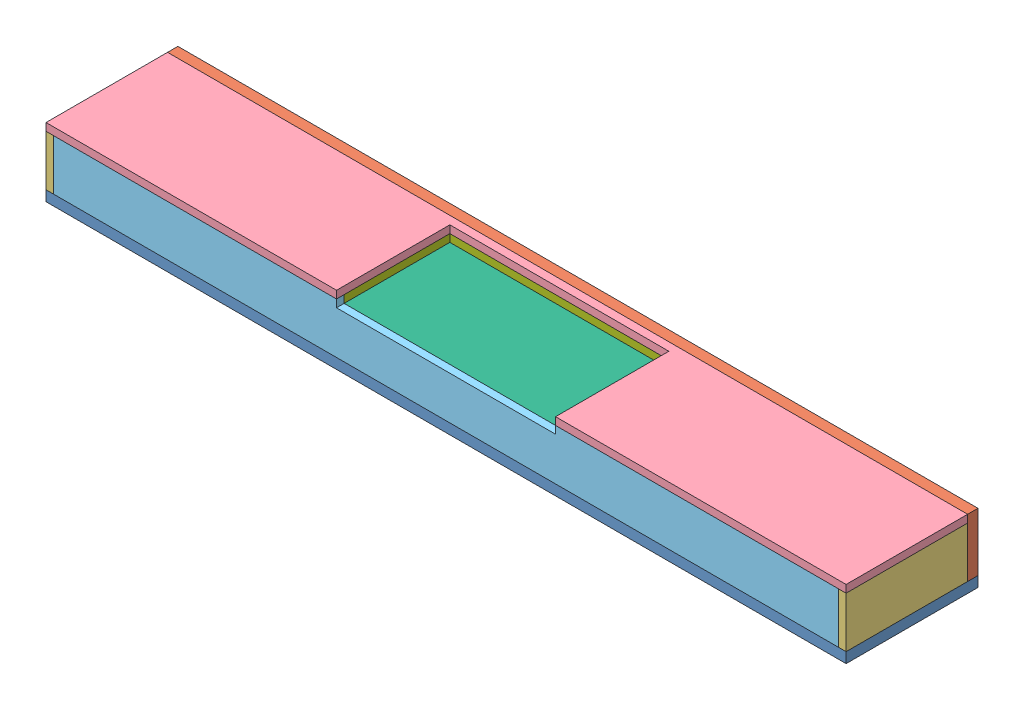
SolidWorks assembly racebaan omhulsel, configuration Default. Lengths in mm.
Overall size (316 27.1 52.1).
8 component instances, 7 part files, 21 mates.
Components (placement in the parent):
- onderstuk racebaan-1: onderstuk racebaan [Default] at (126.0031 144.5271 253.4798) size (316 4.3 52.1)
- zijkant racebaan-1: zijkant racebaan [Default] at (126.0031 156.0271 231.5298) x (1 0 0) z (0 -1 0) size (316 4.3 23)
- doorzichtig zijkant racebaan-1: doorzichtig zijkant racebaan [Default] at (-31.9969 154.5271 255.5298) x (0 0 1) z (0 1 0) size (48 3 20)
- doorzichtig zijkant racebaan-2: doorzichtig zijkant racebaan [Default] at (284.0031 154.5271 255.5298) x (0 0 1) z (0 -1 0) size (48 3 20)
- bovenstuk racebaan-3: bovenstuk racebaan [Default] at (126.0031 164.5271 255.5298) size (316 3 48)
- doorzichtig voorkant racebaan-1: doorzichtig voorkant racebaan [Default] at (126.0031 154.5271 276.5298) x (1 0 0) z (0 -1 0) size (310 3 20)
- plaatje racebaan-1: plaatje racebaan [Default] at (125.7531 158.5271 254.0298) size (92.5 3 45)
- stukje plaat op plaat racebaan-1: stukje plaat op plaat racebaan [Default] at (126.0031 161.5271 270.1173) size (92.5 3 45)
Mates (geometry in assembly coordinates):
- Coincident1: coincident: plane of onderstuk racebaan-1 through (126.0031 144.5271 253.4798) normal (0 1 0); plane of zijkant racebaan-1 through (284.0031 144.5271 227.4298) normal (0 -1 0)
- Coincident2: coincident: plane of onderstuk racebaan-1 through (284.0031 140.4271 279.5298) normal (1 0 0); plane of zijkant racebaan-1 through (284.0031 144.5271 227.4298) normal (1 0 0)
- Coincident3: coincident: plane of onderstuk racebaan-1 through (284.0031 140.4271 227.4298) normal (0 0 -1); plane of zijkant racebaan-1 through (126.0031 156.0271 227.4298) normal (0 0 -1)
- Coincident6: coincident: plane of onderstuk racebaan-1 through (-31.9969 140.4271 279.5298) normal (-1 0 0); plane of doorzichtig zijkant racebaan-1 through (-31.9969 154.5271 255.5298) normal (-1 0 0)
- Coincident7: coincident: plane of zijkant racebaan-1 through (126.0031 156.0271 231.5298) normal (0 0 1); plane of doorzichtig zijkant racebaan-1 through (-28.9969 164.5271 231.5298) normal (0 0 -1)
- Coincident8: coincident: plane of onderstuk racebaan-1 through (126.0031 144.5271 253.4798) normal (0 1 0); plane of doorzichtig zijkant racebaan-1 through (-28.9969 144.5271 279.5298) normal (0 -1 0)
- Coincident9: coincident: plane of onderstuk racebaan-1 through (284.0031 140.4271 279.5298) normal (0 0 1); plane of doorzichtig zijkant racebaan-2 through (281.0031 144.5271 279.5298) normal (0 0 1)
- Coincident10: coincident: plane of onderstuk racebaan-1 through (284.0031 140.4271 279.5298) normal (1 0 0); plane of doorzichtig zijkant racebaan-2 through (284.0031 154.5271 255.5298) normal (1 0 0)
- Coincident11: coincident: plane of onderstuk racebaan-1 through (126.0031 144.5271 253.4798) normal (0 1 0); plane of doorzichtig zijkant racebaan-2 through (281.0031 144.5271 279.5298) normal (0 -1 0)
- Coincident12: coincident: plane of onderstuk racebaan-1 through (284.0031 140.4271 279.5298) normal (0 0 1); plane of bovenstuk racebaan-3 through (284.0031 167.5271 279.5298) normal (0 0 1)
- Coincident13: coincident: plane of doorzichtig zijkant racebaan-1 through (-31.9969 154.5271 255.5298) normal (-1 0 0); plane of bovenstuk racebaan-3 through (-31.9969 167.5271 279.5298) normal (-1 0 0)
- Coincident14: coincident: plane of zijkant racebaan-1 through (284.0031 167.5271 227.4298) normal (0 1 0); plane of bovenstuk racebaan-3 through (126.0031 167.5271 255.5298) normal (0 1 0)
- Coincident15: coincident: plane of onderstuk racebaan-1 through (126.0031 144.5271 253.4798) normal (0 1 0); plane of doorzichtig voorkant racebaan-1 through (281.0031 144.5271 279.5298) normal (0 -1 0)
- Coincident16: coincident: plane of doorzichtig zijkant racebaan-2 through (281.0031 154.5271 255.5298) normal (-1 0 0); plane of doorzichtig voorkant racebaan-1 through (281.0031 144.5271 279.5298) normal (1 0 0)
- Coincident17: coincident: plane of onderstuk racebaan-1 through (284.0031 140.4271 279.5298) normal (0 0 1); plane of doorzichtig voorkant racebaan-1 through (126.0031 154.5271 279.5298) normal (0 0 1)
- Coincident20: coincident: plane of doorzichtig voorkant racebaan-1 through (82.7531 161.5271 279.5298) normal (0 1 0); plane of plaatje racebaan-1 through (125.7531 161.5271 254.0298) normal (0 1 0)
- Coincident21: coincident: plane of doorzichtig voorkant racebaan-1 through (126.0031 154.5271 276.5298) normal (0 0 -1); plane of plaatje racebaan-1 through (172.0031 161.5271 276.5298) normal (0 0 1)
- Distance1: distance = 3.25 mm: plane of doorzichtig voorkant racebaan-1 through (82.7531 164.5271 279.5298) normal (1 0 0); plane of plaatje racebaan-1 through (79.5031 161.5271 276.5298) normal (-1 0 0)
- Coincident22: coincident: plane of bovenstuk racebaan-3 through (126.0031 164.5271 255.5298) normal (0 -1 0); plane of stukje plaat op plaat racebaan-1 through (126.0031 164.5271 270.1173) normal (0 1 0)
- Coincident25: coincident: line of plaatje racebaan-1 through (79.5031 161.5271 276.5298) axis (1 0 0); plane of stukje plaat op plaat racebaan-1 through (169.2531 164.5271 276.5298) normal (0 0 1)
- Coincident27: coincident: plane of bovenstuk racebaan-3 through (82.7531 167.5271 279.5298) normal (1 0 0); plane of stukje plaat op plaat racebaan-1 through (82.7531 164.5271 276.5298) normal (1 0 0)
